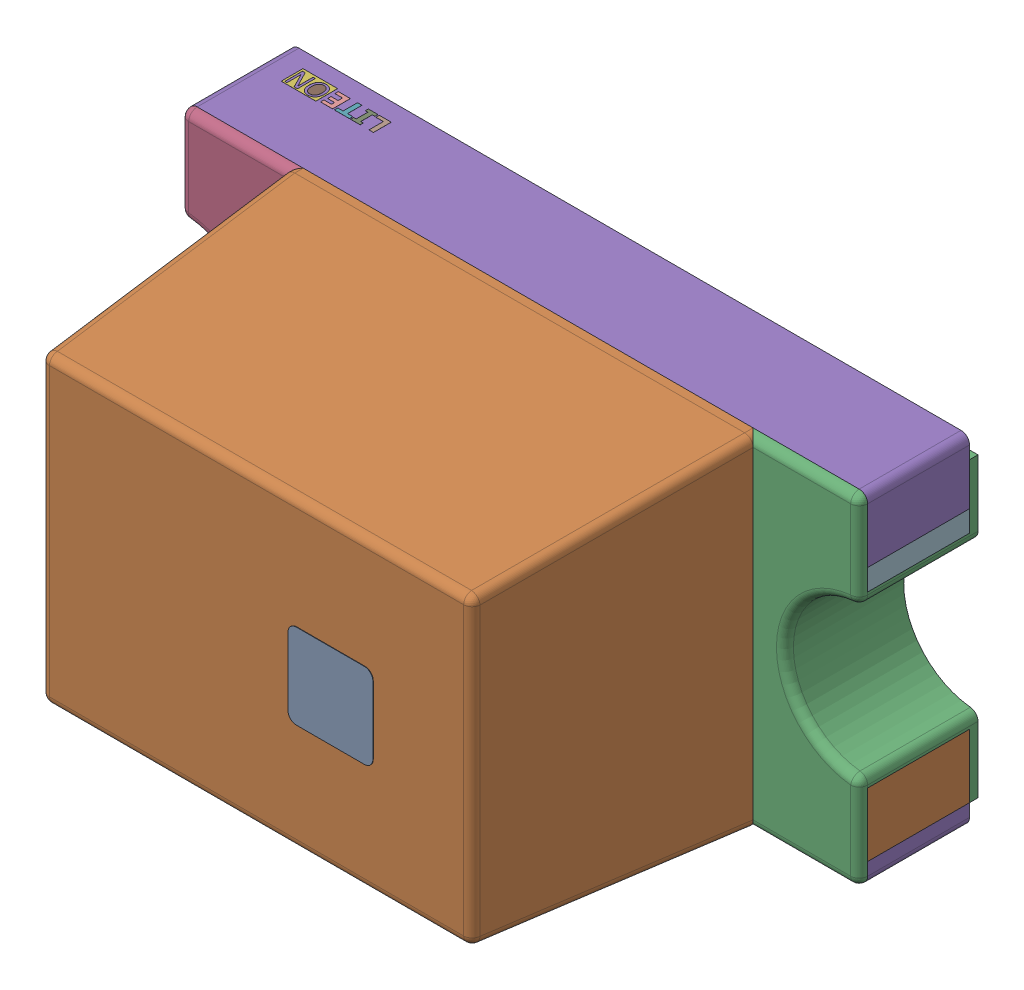
SolidWorks assembly LED1.step, configuration Default. Lengths in mm.
Overall size (1.6 0.8 0.9).
8 component instances, 7 part files, 0 mates.
Components (placement in the parent):
- Diode_Lite-On_LTST-C190GKT_eec.step-1: Diode_Lite-On_LTST-C190GKT_eec.step [Default] at (47.752 64.643 0) x (-1 0 0) z (0 0 1) size (1.6 0.8 0.9)
  - 1-4.step-1: 1-4.step [Default] at (-0.1749 0.0038 0.001) size (0.2 0.2 0.05)
  - 2-5.step-1: 2-5.step [Default] at origin size (1.1 0.8 0.64)
  - 3-6.step-1: 3-6.step [Default] at origin size (1.6 0.8 0.28)
  - 4.step-1: 4.step [Default] at origin size (1.6 0.8 0.24)
  - Lite-On_Logo_Adjustable.step-1: Lite-On_Logo_Adjustable.step [Default] at (-0.9132 -0.3001 -1.9175) x (1 0 0) z (0 -1 0) size (0.21 0.05 0.1)
  - 5.step-1: 5.step [Default] at origin size (1.6 0.7 0.24)
  - 6.step-1: 6.step [Default] at origin size (1.6 0.15 0.24)
